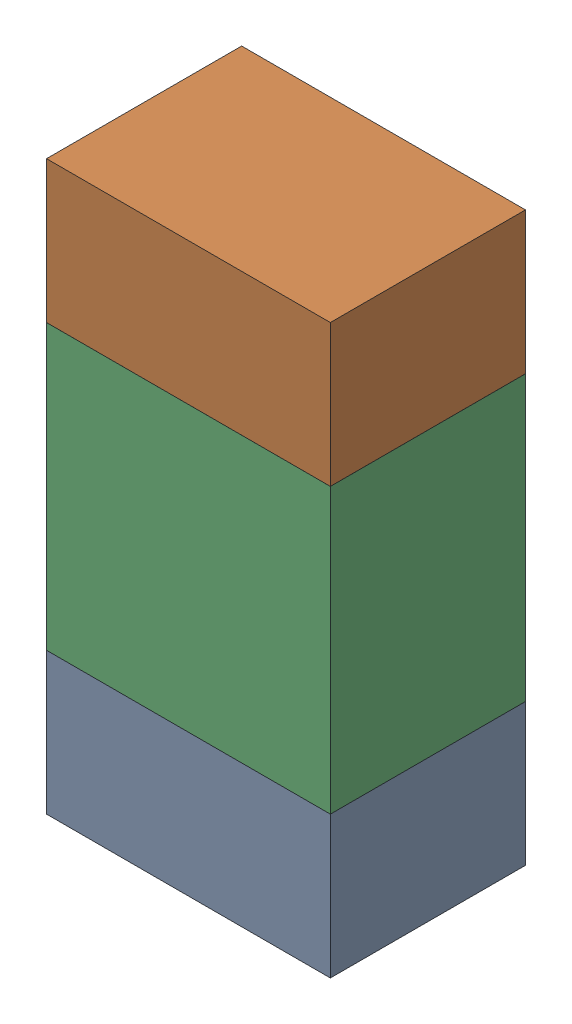
SolidWorks assembly R61, configuration ﾃﾞﾌｫﾙﾄ. Lengths in mm.
Overall size (0.8 1.6 0.55).
6 component instances, 2 part files, 0 mates.
Components (placement in the parent):
- 689261784-1: 689261784 [ﾃﾞﾌｫﾙﾄ] at (44.1999 32.4001 0) size (0.8 0.4 0.55)
  - Extruded_34-1: Extruded_34 [ﾃﾞﾌｫﾙﾄ] at origin size (0.8 0.4 0.55)
- 689261784-2: 689261784 [ﾃﾞﾌｫﾙﾄ] at (44.1999 33.6001 0) size (0.8 0.4 0.55)
  - Extruded_34-1: Extruded_34 [ﾃﾞﾌｫﾙﾄ] at origin size (0.8 0.4 0.55)
- 689261648-1: 689261648 [ﾃﾞﾌｫﾙﾄ] at (44.1999 33 0) size (0.8 0.8 0.55)
  - Extruded_33-1: Extruded_33 [ﾃﾞﾌｫﾙﾄ] at origin size (0.8 0.8 0.55)
